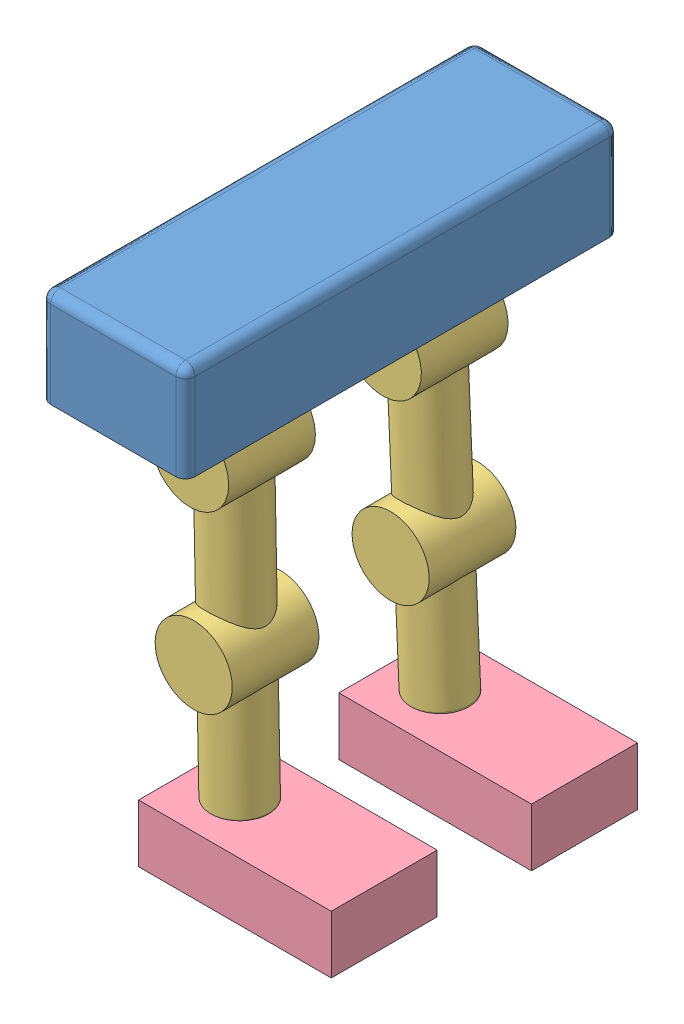
SolidWorks assembly Assem-11, configuration Default. Lengths in mm.
Overall size (23.93 53.99 45).
7 component instances, 4 part files, 14 mates.
Components (placement in the parent):
- Part1-2: Part1 [Default] at (3.4987 28.6931 34.0618) x (0 0 -1) z (1 0 0) size (45 10 15)
- Part2-2: Part2 [Default] at (10.9987 15.1931 24.0618) x (-1 0 0) z (0 0 -1) size (6 6.59 6)
- Part2-3: Part2 [Default] at (10.9987 15.1931 44.0618) x (-1 0 0) z (0 0 -1) size (6 6.59 6)
- Part3-1: Part3 [Default] at (10.9987 15.1931 44.0618) x (0.9998 0.020022 0) z (0 0 1) size (8 39 9)
- Part3-2: Part3 [Default] at (10.9987 15.1931 24.0618) x (0.999007 0.044546 0) z (0 0 1) size (8 39 9)
- Part4-5: Part4 [Default] at (16.6394 -22.8005 44.0618) size (20 6 11)
- Part4-6: Part4 [Default] at (17.4242 -22.7751 24.0618) size (20 6 11)
Mates (geometry in assembly coordinates):
- Concentric1: concentric: sphere of Part1-2; sphere of Part2-3
- Concentric2: concentric: sphere of Part1-2; sphere of Part2-2
- Lock1: lock: unknown of Part1-2; unknown of Part2-3
- Lock2: lock: unknown of Part1-2; unknown of Part2-2
- Concentric3: concentric aligned: cylinder of Part2-3 through (10.9987 15.1931 47.0618) axis (0 0 -1) radius 4; cylinder of Part3-1 through (10.9987 15.1931 48.5618) axis (0 0 -1) radius 4
- Distance1: distance = 8 mm aligned: plane of Part1-2 through (18.4987 21.1931 56.5618) normal (0 0 1); plane of Part3-1 through (10.9987 15.1931 48.5618) normal (0 0 1)
- Concentric4: concentric aligned: cylinder of Part2-2 through (10.9987 15.1931 27.0618) axis (0 0 -1) radius 4; cylinder of Part3-2 through (10.9987 15.1931 28.5618) axis (0 0 -1) radius 4
- Distance2: distance = 8 mm aligned: plane of Part3-2 through (10.9987 15.1931 19.5618) normal (0 0 -1); plane of Part1-2 through (18.4987 21.1931 11.5618) normal (0 0 -1)
- Concentric10: concentric: sphere of Part3-1; sphere of Part4-5
- Parallel12: parallel aligned: plane of Part1-2 through (18.4987 21.1931 56.5618) normal (0 0 1); plane of Part4-5 through (6.6394 -16.8005 49.5618) normal (0 0 1)
- Parallel13: parallel aligned: plane of Part1-2 through (3.4987 31.1931 34.0618) normal (0 1 0); plane of Part4-5 through (16.6394 -16.8005 44.0618) normal (0 1 0)
- Concentric11: concentric: sphere of Part3-2; sphere of Part4-6
- Parallel14: parallel aligned: plane of Part1-2 through (3.4987 31.1931 34.0618) normal (0 1 0); plane of Part4-6 through (17.4242 -16.7751 24.0618) normal (0 1 0)
- Parallel15: parallel aligned: plane of Part1-2 through (18.4987 21.1931 56.5618) normal (0 0 1); plane of Part4-6 through (7.4242 -16.7751 29.5618) normal (0 0 1)
